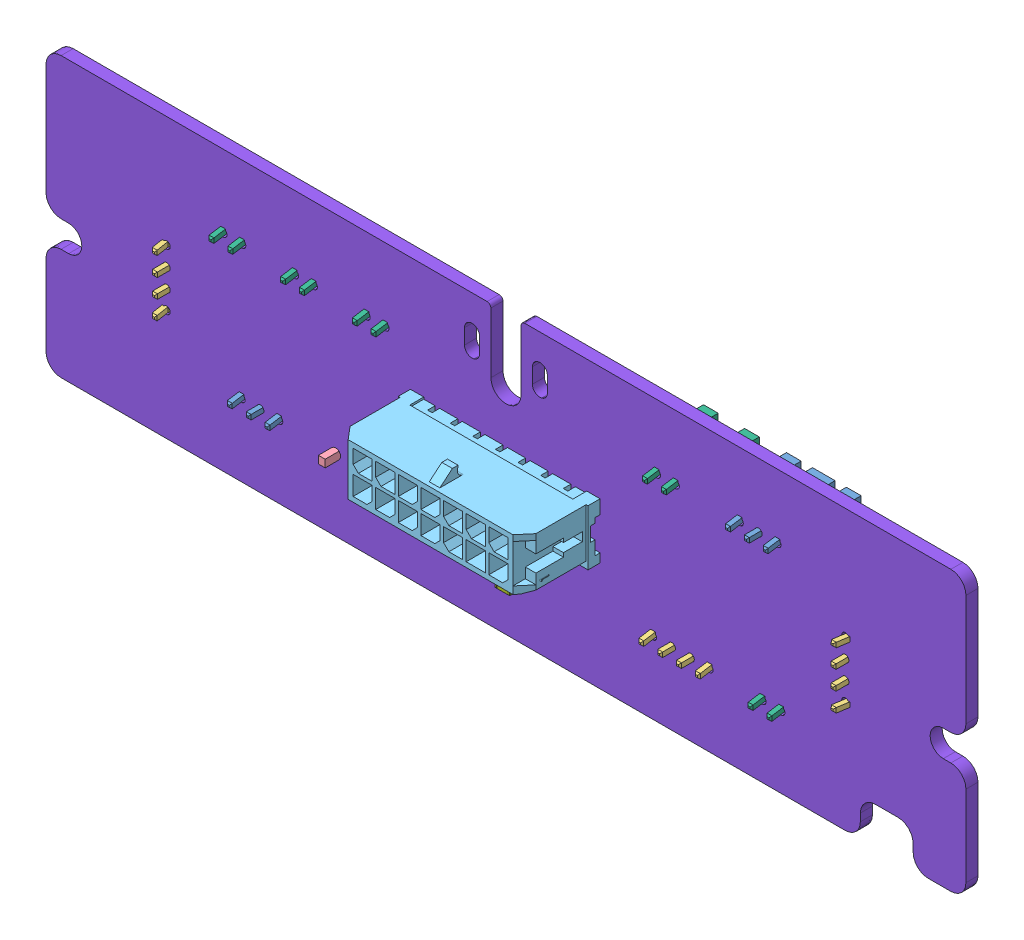
SolidWorks assembly V0-UmbilicalBoardRevA, configuration Default. Lengths in mm.
Overall size (122 37 25.45).
33 component instances, 8 part files, 0 mates.
Components (placement in the parent):
- Copy of JST_XH_B3B-XH-A_1x03_P2.50mm_Vertical^V0-UmbilicalBoardRevA-1: Copy of JST_XH_B3B-XH-A_1x03_P2.50mm_Vertical^V0-UmbilicalBoardRevA [Default] at (69.928 -108.89 -0.05) x (-1 0 0) z (0 0 -1) size (9.9 5.75 10.4) (virtual)
  - SOLID^Copy of JST_XH_B3B-XH-A_1x03_P2.50mm_Vertical_V0-UmbilicalBoardRevA-1: SOLID^Copy of JST_XH_B3B-XH-A_1x03_P2.50mm_Vertical_V0-UmbilicalBoardRevA [Default] at origin size (9.9 5.75 10.4) (virtual)
- Copy of C_0805_2012Metric^V0-UmbilicalBoardRevA-1: Copy of C_0805_2012Metric^V0-UmbilicalBoardRevA [Default] at (60 -101 -0.05) x (0 -1 0) z (0 0 -1) size (2 1.25 1.25) (virtual)
  - SOLID-0^Copy of C_0805_2012Metric_V0-UmbilicalBoardRevA-1: SOLID-0^Copy of C_0805_2012Metric_V0-UmbilicalBoardRevA [Default] at origin size (2 1.25 1.25) (virtual)
- Copy of C_0805_2012Metric^V0-UmbilicalBoardRevA-2: Copy of C_0805_2012Metric^V0-UmbilicalBoardRevA [Default] at (132.1625 -96.4 -0.05) x (-1 0 0) z (0 0 -1) size (2 1.25 1.25) (virtual)
  - SOLID-0^Copy of C_0805_2012Metric_V0-UmbilicalBoardRevA-1: SOLID-0^Copy of C_0805_2012Metric_V0-UmbilicalBoardRevA [Default] at origin size (2 1.25 1.25) (virtual)
- Copy of C_0805_2012Metric^V0-UmbilicalBoardRevA-3: Copy of C_0805_2012Metric^V0-UmbilicalBoardRevA [Default] at (139.6 -97.3625 -0.05) x (0 1 0) z (0 0 -1) size (2 1.25 1.25) (virtual)
  - SOLID-0^Copy of C_0805_2012Metric_V0-UmbilicalBoardRevA-1: SOLID-0^Copy of C_0805_2012Metric_V0-UmbilicalBoardRevA [Default] at origin size (2 1.25 1.25) (virtual)
- Copy of JST_XH_B4B-XH-A_1x04_P2.50mm_Vertical^V0-UmbilicalBoardRevA-1: Copy of JST_XH_B4B-XH-A_1x04_P2.50mm_Vertical^V0-UmbilicalBoardRevA [Default] at (55 -96.25 -0.05) x (0 -1 0) z (0 0 -1) size (12.4 5.75 10.4) (virtual)
  - SOLID-1^Copy of JST_XH_B4B-XH-A_1x04_P2.50mm_Vertical_V0-UmbilicalBoardRevA-1: SOLID-1^Copy of JST_XH_B4B-XH-A_1x04_P2.50mm_Vertical_V0-UmbilicalBoardRevA [Default] at origin size (12.4 5.75 10.4) (virtual)
- Copy of JST_XH_B4B-XH-A_1x04_P2.50mm_Vertical^V0-UmbilicalBoardRevA-2: Copy of JST_XH_B4B-XH-A_1x04_P2.50mm_Vertical^V0-UmbilicalBoardRevA [Default] at (145 -103.75 -0.05) x (0 1 0) z (0 0 -1) size (12.4 5.75 10.4) (virtual)
  - SOLID-1^Copy of JST_XH_B4B-XH-A_1x04_P2.50mm_Vertical_V0-UmbilicalBoardRevA-1: SOLID-1^Copy of JST_XH_B4B-XH-A_1x04_P2.50mm_Vertical_V0-UmbilicalBoardRevA [Default] at origin size (12.4 5.75 10.4) (virtual)
- Copy of JST_XH_B3B-XH-A_1x03_P2.50mm_Vertical^V0-UmbilicalBoardRevA-2: Copy of JST_XH_B3B-XH-A_1x03_P2.50mm_Vertical^V0-UmbilicalBoardRevA [Default] at (136 -90 -0.05) x (-1 0 0) z (0 0 -1) size (9.9 5.75 10.4) (virtual)
  - SOLID^Copy of JST_XH_B3B-XH-A_1x03_P2.50mm_Vertical_V0-UmbilicalBoardRevA-1: SOLID^Copy of JST_XH_B3B-XH-A_1x03_P2.50mm_Vertical_V0-UmbilicalBoardRevA [Default] at origin size (9.9 5.75 10.4) (virtual)
- Copy of TerminalBlock_Phoenix_MKDS-1,5-2-5.08_1x02_P5.08mm_Horizontal^V0-UmbilicalBoardRevA-1: Copy of TerminalBlock_Phoenix_MKDS-1,5-2-5.08_1x02_P5.08mm_Horizontal^V0-UmbilicalBoardRevA [Default] at (77.42 -109 -0.05) x (1 0 0) z (0 0 -1) size (10.9 9.8 17.3) (virtual)
  - SOLID-2^Copy of TerminalBlock_Phoenix_MKDS-1,5-2-5.08_1x02_P5.08mm_Horizontal_V0-UmbilicalBoardRevA-1: SOLID-2^Copy of TerminalBlock_Phoenix_MKDS-1,5-2-5.08_1x02_P5.08mm_Horizontal_V0-UmbilicalBoardRevA [Default] at origin size (10.9 9.8 17.3) (virtual)
- Copy of JST_XH_B4B-XH-A_1x04_P2.50mm_Vertical^V0-UmbilicalBoardRevA-3: Copy of JST_XH_B4B-XH-A_1x04_P2.50mm_Vertical^V0-UmbilicalBoardRevA [Default] at (127 -108.89 -0.05) x (-1 0 0) z (0 0 -1) size (12.4 5.75 10.4) (virtual)
  - SOLID-1^Copy of JST_XH_B4B-XH-A_1x04_P2.50mm_Vertical_V0-UmbilicalBoardRevA-1: SOLID-1^Copy of JST_XH_B4B-XH-A_1x04_P2.50mm_Vertical_V0-UmbilicalBoardRevA [Default] at origin size (12.4 5.75 10.4) (virtual)
- Copy of Molex_Micro-Fit_3.0_43045-1412_2x07_P3.00mm_Vertical^V0-UmbilicalBoardRevA-1: Copy of Molex_Micro-Fit_3.0_43045-1412_2x07_P3.00mm_Vertical^V0-UmbilicalBoardRevA [Default] at (100 -100 6.65) size (25.15 8.77 13.09) (virtual)
  - SOLID-3^Copy of Molex_Micro-Fit_3.0_43045-1412_2x07_P3.00mm_Vertical_V0-UmbilicalBoardRevA-1: SOLID-3^Copy of Molex_Micro-Fit_3.0_43045-1412_2x07_P3.00mm_Vertical_V0-UmbilicalBoardRevA [Default] at origin size (25.15 8.77 13.09) (virtual)
- Copy of JST_XH_B2B-XH-A_1x02_P2.50mm_Vertical^V0-UmbilicalBoardRevA-1: Copy of JST_XH_B2B-XH-A_1x02_P2.50mm_Vertical^V0-UmbilicalBoardRevA [Default] at (136.5 -109 -0.05) x (-1 0 0) z (0 0 -1) size (7.4 5.75 10.4) (virtual)
  - SOLID-4^Copy of JST_XH_B2B-XH-A_1x02_P2.50mm_Vertical_V0-UmbilicalBoardRevA-1: SOLID-4^Copy of JST_XH_B2B-XH-A_1x02_P2.50mm_Vertical_V0-UmbilicalBoardRevA [Default] at origin size (7.4 5.75 10.4) (virtual)
- Copy of JST_XH_B2B-XH-A_1x02_P2.50mm_Vertical^V0-UmbilicalBoardRevA-2: Copy of JST_XH_B2B-XH-A_1x02_P2.50mm_Vertical^V0-UmbilicalBoardRevA [Default] at (122.5 -90 -0.05) x (-1 0 0) z (0 0 -1) size (7.4 5.75 10.4) (virtual)
  - SOLID-4^Copy of JST_XH_B2B-XH-A_1x02_P2.50mm_Vertical_V0-UmbilicalBoardRevA-1: SOLID-4^Copy of JST_XH_B2B-XH-A_1x02_P2.50mm_Vertical_V0-UmbilicalBoardRevA [Default] at origin size (7.4 5.75 10.4) (virtual)
- Copy of JST_XH_B2B-XH-A_1x02_P2.50mm_Vertical^V0-UmbilicalBoardRevA-3: Copy of JST_XH_B2B-XH-A_1x02_P2.50mm_Vertical^V0-UmbilicalBoardRevA [Default] at (65 -91.11 -0.05) x (-1 0 0) z (0 0 -1) size (7.4 5.75 10.4) (virtual)
  - SOLID-4^Copy of JST_XH_B2B-XH-A_1x02_P2.50mm_Vertical_V0-UmbilicalBoardRevA-1: SOLID-4^Copy of JST_XH_B2B-XH-A_1x02_P2.50mm_Vertical_V0-UmbilicalBoardRevA [Default] at origin size (7.4 5.75 10.4) (virtual)
- Copy of JST_XH_B2B-XH-A_1x02_P2.50mm_Vertical^V0-UmbilicalBoardRevA-4: Copy of JST_XH_B2B-XH-A_1x02_P2.50mm_Vertical^V0-UmbilicalBoardRevA [Default] at (84 -91.11 -0.05) x (-1 0 0) z (0 0 -1) size (7.4 5.75 10.4) (virtual)
  - SOLID-4^Copy of JST_XH_B2B-XH-A_1x02_P2.50mm_Vertical_V0-UmbilicalBoardRevA-1: SOLID-4^Copy of JST_XH_B2B-XH-A_1x02_P2.50mm_Vertical_V0-UmbilicalBoardRevA [Default] at origin size (7.4 5.75 10.4) (virtual)
- Copy of JST_XH_B2B-XH-A_1x02_P2.50mm_Vertical^V0-UmbilicalBoardRevA-5: Copy of JST_XH_B2B-XH-A_1x02_P2.50mm_Vertical^V0-UmbilicalBoardRevA [Default] at (74.5 -91.11 -0.05) x (-1 0 0) z (0 0 -1) size (7.4 5.75 10.4) (virtual)
  - SOLID-4^Copy of JST_XH_B2B-XH-A_1x02_P2.50mm_Vertical_V0-UmbilicalBoardRevA-1: SOLID-4^Copy of JST_XH_B2B-XH-A_1x02_P2.50mm_Vertical_V0-UmbilicalBoardRevA [Default] at origin size (7.4 5.75 10.4) (virtual)
- Copy of R_0805_2012Metric^V0-UmbilicalBoardRevA-1: Copy of R_0805_2012Metric^V0-UmbilicalBoardRevA [Default] at (100 -112.7 1.65) size (2 1.2 0.45) (virtual)
  - SOLID-5^Copy of R_0805_2012Metric_V0-UmbilicalBoardRevA-1: SOLID-5^Copy of R_0805_2012Metric_V0-UmbilicalBoardRevA [Default] at origin size (2 1.2 0.45) (virtual)
- Copy of COMPOUND^V0-UmbilicalBoardRevA-1: Copy of COMPOUND^V0-UmbilicalBoardRevA [Default] at origin size (122 37 1.6) (virtual)
